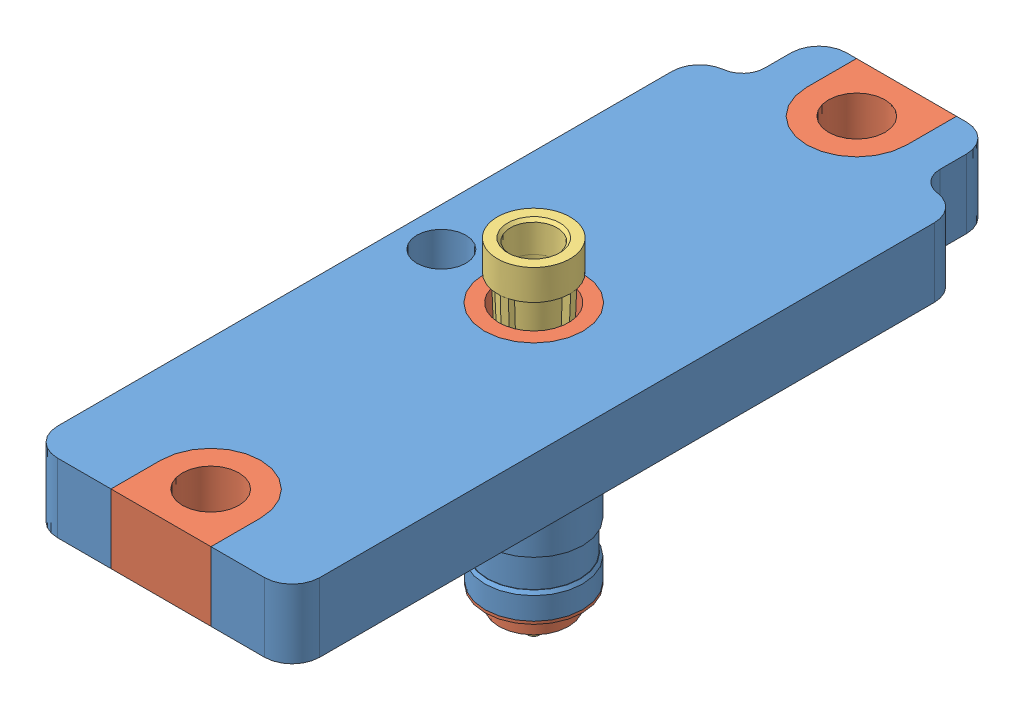
SolidWorks assembly New Mount Needle holder Assembly r1, configuration Default. Lengths in mm.
Overall size (24.28 31.44 68.58).
3 component instances, 3 part files, 2 mates.
Components (placement in the parent):
- New Mount Needle holder standard r1-1: New Mount Needle holder standard r1 [Default] at origin size (24.28 22.21 68.58)
- New Mount Needle holder conductive r1-1: New Mount Needle holder conductive r1 [Default] at origin size (9.2 24.22 68.58)
- Qosina 11077-1: Qosina 11077 [Default] at (12.065 -19.86 -34.29) x (0.149921 0 0.988698) z (0 1 0) size (6.81 6.81 31.44)
Mates (geometry in assembly coordinates):
- Concentric2: concentric aligned: circle of Qosina 11077-1; circle of New Mount Needle holder conductive r1-1
- Distance2: distance = 2 mm aligned: plane of Qosina 11077-1 through (12.065 -19.86 -34.29) normal (0 -1 0); plane of New Mount Needle holder conductive r1-1 through (12.065 -17.86 -34.29) normal (0 -1 0)
